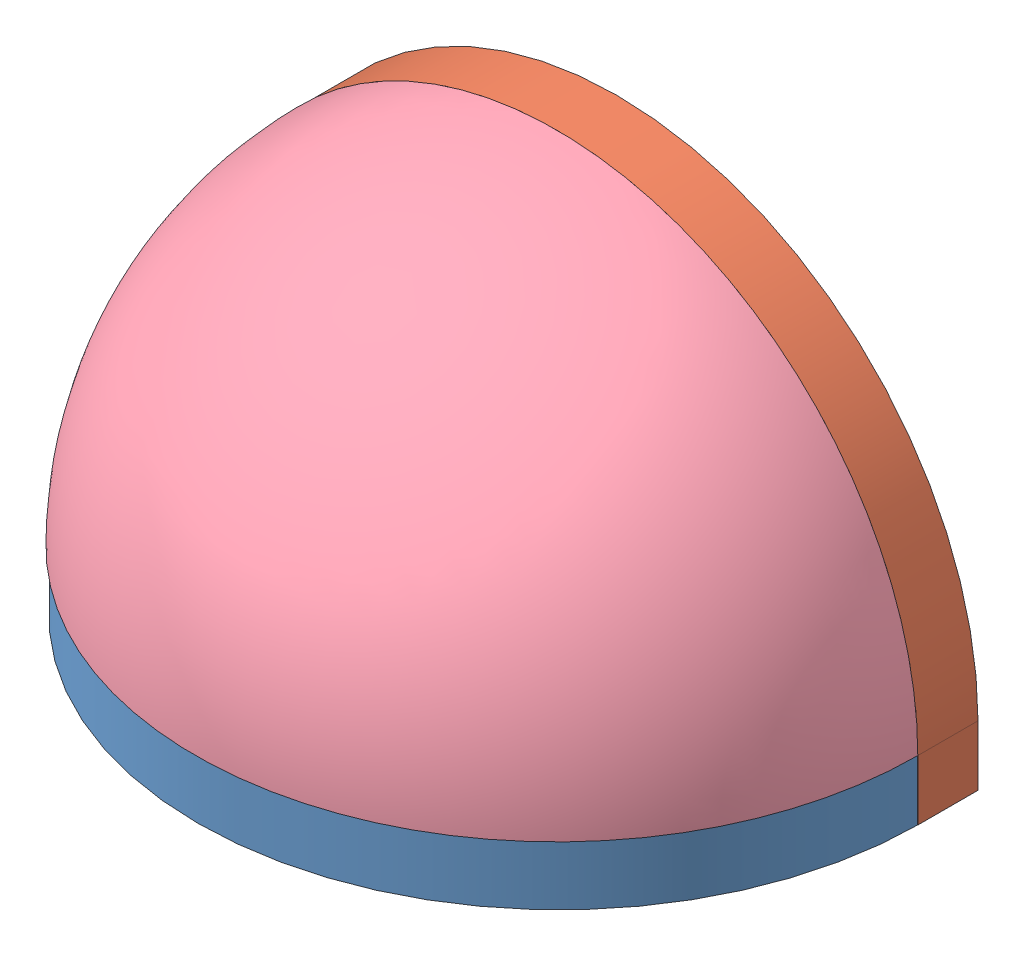
SolidWorks assembly lampara, configuration Predeterminado. Lengths in mm.
Overall size (60 35 35).
5 component instances, 4 part files, 6 mates.
Components (placement in the parent):
- base-1: base [Predeterminado] at origin size (60 5 30)
- base2-1: base2 [Predeterminado] at (0 5 -4.7773) size (60 35 5)
- b1-2: b1 [Predeterminado] at (12.1564 5.7366 12.0951) x (0.707107 0 -0.707107) z (0.707107 0 0.707107) size (10 10.74 15.74)
- b1-3: b1 [Predeterminado] at (-12.1564 5.7366 12.0951) x (0.707107 0 0.707107) z (-0.707107 0 0.707107) size (10 10.74 15.74)
- cupula-1: cupula [Predeterminado] at (0 5 0.2227) size (60 30 30)
Mates (geometry in assembly coordinates):
- Coincidente1: coincident aligned: plane of base-1 through (0 0 0) normal (0 -1 0); plane of base2-1 through (-30 0 0.2227) normal (0 -1 0)
- Tangente1: tangent aligned: cylinder of base-1 through (0 5 0) axis (0 -1 0) radius 30; plane of base2-1 through (30 0 0.2227) normal (1 0 0)
- Coincidente2: coincident anti-aligned: plane of base-1 through (0 5 0) normal (0 1 0); plane of b1-2 through (12.1564 5 12.0951) normal (0 -1 0)
- Coincidente3: coincident anti-aligned: plane of base-1 through (0 5 0) normal (0 1 0); plane of cupula-1 through (0 5 0.2227) normal (0 -1 0)
- Coincidente4: coincident anti-aligned: plane of base2-1 through (0 5 0.2227) normal (0 0 1); plane of cupula-1 through (0 5 0.2227) normal (0 0 -1)
- Tangente2: tangent aligned: plane of base2-1 through (30 0 0.2227) normal (1 0 0); sphere of cupula-1
